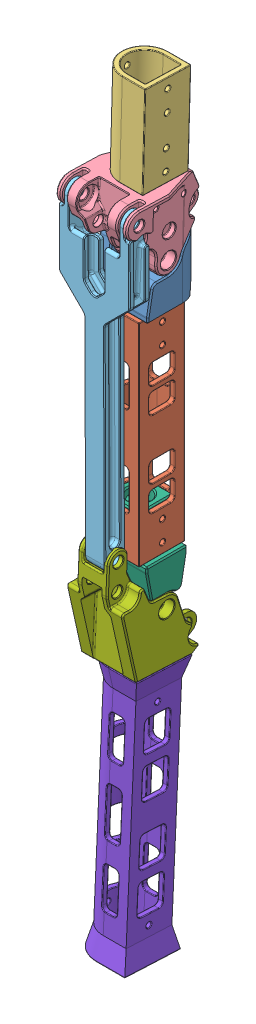
SolidWorks assembly AARL_QR_FR_LE_PL_BL_20_10_Assembly_part, configuration Default. Lengths in mm.
Overall size (44.52 477.31 62.43).
8 component instances, 8 part files, 16 mates.
Components (placement in the parent):
- AARL_Puppy_18_01_04_039_R-1: AARL_Puppy_18_01_04_039_R [Default] at (-100.6976 56.246 95.3837) size (35.13 68.01 39.62)
- AARL_QR_FR_LE_PL_BL_20_10_002-1: AARL_QR_FR_LE_PL_BL_20_10_002 [Default] at (-40.3419 -105.2151 95.3837) x (1 0 0) z (0 1 0) size (28.79 28.79 132.68)
- AARL_QR_FR_LE_PL_BL_20_10_003-1: AARL_QR_FR_LE_PL_BL_20_10_003 [Default] at (-39.6291 153.0553 93.0123) x (1 0 0) z (0 -0.999586 0.028786) size (28.79 28.79 57.15)
- AARL_Puppy_18_01_06_042-1: AARL_Puppy_18_01_06_042 [Default] at (-39.773 83.2223 94.6069) x (0 0.028786 0.999586) z (1 0 0) size (58.94 73.03 44.45)
- AARL_Puppy_18_01_06_037-1: AARL_Puppy_18_01_06_037 [Default] at (-39.7015 88.6712 118.374) x (0 -0.999995 -0.003084) z (-1 0 0) size (202.53 15.88 44.45)
- AARL_Puppy_18_01_06_036_L-1: AARL_Puppy_18_01_06_036_L [Default] at (-40.659 -133.9933 95.3837) x (-1 0 0) z (0 0 1) size (35.13 62.12 25.6)
- AARL_Puppy_18_01_06_38-1: AARL_Puppy_18_01_06_38 [Default] at (-40.8007 -133.9933 95.3837) x (0 0.046717 0.998908) z (-1 0 0) size (58.05 95.25 35.13)
- AARL_QR_FR_LE_PL_BL_20_10_004-1: AARL_QR_FR_LE_PL_BL_20_10_004 [Default] at (-41.0188 -178.3938 97.4804) x (1 0 0) z (0 0.046717 0.998908) size (35.89 157.97 36.86)
Mates (geometry in assembly coordinates):
- Concentric6: concentric anti-aligned: cylinder of AARL_Puppy_18_01_04_039_R-1 through (-29.3363 21.1178 95.3837) axis (1 0 0) radius 1.5875; cylinder of AARL_QR_FR_LE_PL_BL_20_10_002-1 through (-14.9419 21.1178 95.3837) axis (-1 0 0) radius 1.5875
- Concentric7: concentric anti-aligned: cylinder of AARL_Puppy_18_01_04_039_R-1 through (-29.3363 8.4178 95.3837) axis (1 0 0) radius 1.5875; cylinder of AARL_QR_FR_LE_PL_BL_20_10_002-1 through (-14.9419 8.4178 95.3837) axis (-1 0 0) radius 1.5875
- Concentric8: concentric anti-aligned: cylinder of AARL_Puppy_18_01_04_039_R-1 through (-22.6053 56.246 95.3837) axis (-1 0 0) radius 3.2385; cylinder of AARL_Puppy_18_01_06_042-1 through (-62.948 56.246 95.3837) axis (1 0 0) radius 4.826
- Concentric9: concentric aligned: cylinder of AARL_Puppy_18_01_04_039_R-1 through (-22.6053 56.246 95.3837) axis (-1 0 0) radius 3.2385; cylinder of AARL_Puppy_18_01_06_042-1 through (-8.5589 56.246 95.3837) axis (-1 0 0) radius 4.826
- Concentric10: concentric aligned: cylinder of AARL_QR_FR_LE_PL_BL_20_10_003-1 through (-63.3336 114.9591 93.6929) axis (1 0 0) radius 1.5875; cylinder of AARL_Puppy_18_01_06_042-1 through (-65.173 114.9591 93.6929) axis (1 0 0) radius 1.5875
- Concentric11: concentric aligned: cylinder of AARL_QR_FR_LE_PL_BL_20_10_003-1 through (-63.3336 102.2644 94.0585) axis (1 0 0) radius 1.5875; cylinder of AARL_Puppy_18_01_06_042-1 through (-65.173 102.2644 94.0585) axis (1 0 0) radius 1.5875
- Concentric13: concentric anti-aligned: cylinder of AARL_Puppy_18_01_06_042-1 through (21.7483 88.6712 118.374) axis (-1 0 0) radius 3.175; cylinder of AARL_Puppy_18_01_06_037-1 through (-61.9265 88.6712 118.374) axis (1 0 0) radius 3.2385
- Concentric14: concentric anti-aligned: cylinder of AARL_Puppy_18_01_06_042-1 through (21.7483 88.6712 118.374) axis (-1 0 0) radius 3.175; cylinder of AARL_Puppy_18_01_06_037-1 through (-61.9265 88.6712 118.374) axis (1 0 0) radius 3.2385
- Concentric15: concentric anti-aligned: cylinder of AARL_QR_FR_LE_PL_BL_20_10_002-1 through (-14.9419 -86.1651 95.3837) axis (-1 0 0) radius 1.5875; cylinder of AARL_Puppy_18_01_06_036_L-1 through (-29.8259 -86.1651 95.3837) axis (1 0 0) radius 1.5875
- Concentric16: concentric anti-aligned: cylinder of AARL_QR_FR_LE_PL_BL_20_10_002-1 through (-14.9419 -98.8651 95.3837) axis (-1 0 0) radius 1.5875; cylinder of AARL_Puppy_18_01_06_036_L-1 through (-29.8259 -98.8651 95.3837) axis (1 0 0) radius 1.5875
- Concentric19: concentric anti-aligned: cylinder of AARL_Puppy_18_01_06_036_L-1 through (-23.0949 -133.9933 95.3837) axis (-1 0 0) radius 3.2385; cylinder of AARL_Puppy_18_01_06_38-1 through (-58.3648 -133.9933 95.3837) axis (1 0 0) radius 3.2385
- Concentric20: concentric anti-aligned: cylinder of AARL_Puppy_18_01_06_036_L-1 through (-23.0949 -133.9933 95.3837) axis (-1 0 0) radius 3.2385; cylinder of AARL_Puppy_18_01_06_38-1 through (-58.3648 -133.9933 95.3837) axis (1 0 0) radius 3.2385
- Concentric21: concentric aligned: circle of AARL_Puppy_18_01_06_037-1; cylinder of AARL_Puppy_18_01_06_38-1 through (49.8146 -101.1608 117.7884) axis (-1 0 0) radius 3.175
- Coincident2: coincident anti-aligned: plane of AARL_Puppy_18_01_06_38-1 through (-58.3648 -166.5292 79.3221) normal (0 -0.998908 0.046717); plane of AARL_QR_FR_LE_PL_BL_20_10_004-1 through (-41.0188 -165.7077 96.8871) normal (0 0.998908 -0.046717)
- Concentric26: concentric anti-aligned: cylinder of AARL_Puppy_18_01_06_38-1 through (-58.3648 -184.7378 97.7569) axis (1 0 0) radius 1.5875; cylinder of AARL_QR_FR_LE_PL_BL_20_10_004-1 through (-11.3833 -184.7378 97.7569) axis (-1 0 0) radius 1.5875
- Concentric27: concentric anti-aligned: cylinder of AARL_Puppy_18_01_06_38-1 through (-58.3648 -184.7378 97.7569) axis (1 0 0) radius 1.5875; cylinder of AARL_QR_FR_LE_PL_BL_20_10_004-1 through (-11.3833 -184.7378 97.7569) axis (-1 0 0) radius 1.5875
